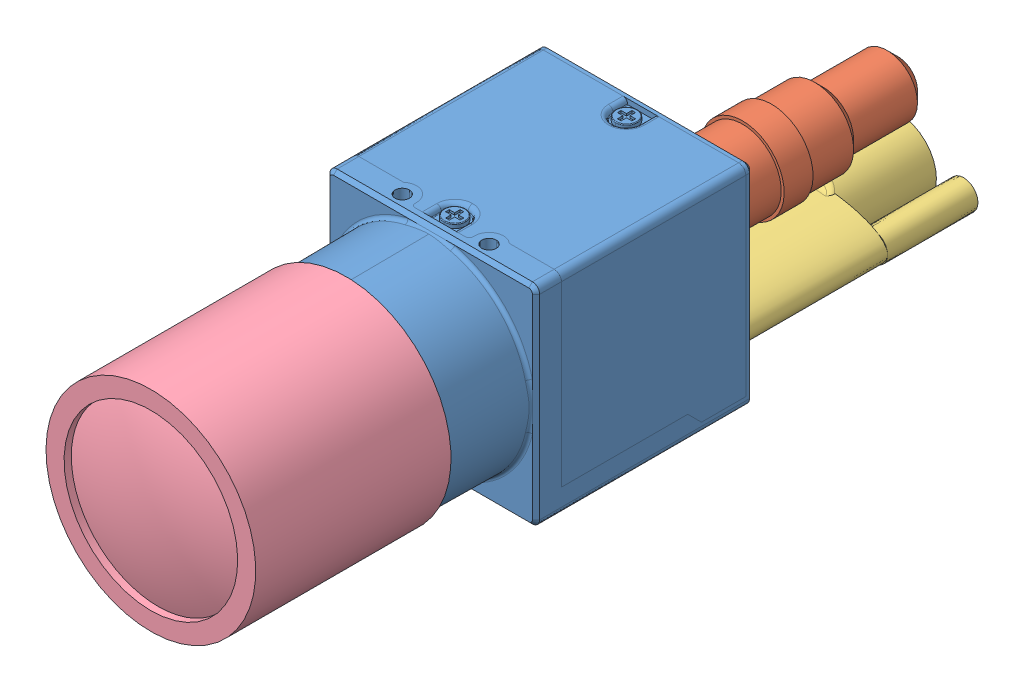
SolidWorks assembly BFS_U3_pinhole, configuration Default. Lengths in mm.
Overall size (36.71 36.71 104.36).
4 component instances, 4 part files, 9 mates.
Components (placement in the parent):
- FL2-020-R0-1: FL2-020-R0 [Default] at origin size (29 29 47.76)
- round_connector-1: round_connector [Default] at (7.25 7.25 -17.9182) x (0 0 -1) z (-0.517634 -0.855602 0) size (26.5 11.5 11.5)
- wide_connector-1: wide_connector [Default] at (0 -9.325 -18.2182) x (1 0 0) z (0 0 -1) size (22 10.5 33.5)
- Tamron_M118FM08-1: Tamron_M118FM08 [Default] at (0 0 36.6398) x (0.317874 -0.948133 0) z (0 0 1) size (29 29 34.1)
Mates (geometry in assembly coordinates):
- Coincident1: coincident anti-aligned: plane of FL2-020-R0_V2.step-1 through (-10 -7.325 -18.2182) normal (0 0 -1); plane of wide_connector-1 through (0 -9.325 -18.2182) normal (0 0 1)
- Concentric1: concentric anti-aligned: cylinder of FL2-020-R0_V2.step-1 through (-9 -9.325 -18.2182) axis (0 0 -1) radius 1; cylinder of wide_connector-1 through (-9 -9.325 -51.7182) axis (0 0 1) radius 2
- Concentric3: concentric anti-aligned: cylinder of FL2-020-R0_V2.step-1 through (9 -9.325 -18.2182) axis (0 0 -1) radius 1; cylinder of wide_connector-1 through (9 -9.325 -51.7182) axis (0 0 1) radius 2
- Concentric5: concentric aligned: circle of FL2-020-R0_V2.step-1; circle of round_connector-1
- Coincident3: coincident anti-aligned: plane of FL2-020-R0_V2.step-1 through (7.25 7.25 -17.9182) normal (0 0 -1); plane of round_connector-1 through (11.8275 4.4807 -17.9182) normal (0 0 1)
- Concentric6: concentric: cylinder of FL2-020-R0-1 through (0 0 22.9747) axis (0 0 1) radius 12.7; cylinder of FE185C086HA_1-1 through (0 0 28.9267) axis (0 0 -1) radius 11.2
- Coincident5: coincident anti-aligned: plane of FL2-020-R0-1 through (0 13.5741 24.6398) normal (0 0 1); plane of FE185C086HA_1-1 through (0 0 37.2267) normal (0 0 -1)
- Concentric7: concentric anti-aligned: cone of FL2-020-R0-1 through (0 0 13.132) axis (0 0 1); cylinder of Tamron_M111FM08_8mm-1 through (0 0 18.5398) axis (0 0 -1) radius 14.5
- Coincident6: coincident anti-aligned: plane of FL2-020-R0-1 through (0 13.5741 24.6398) normal (0 0 1); plane of Tamron_M111FM08_8mm-1 through (13.7479 4.6092 24.6398) normal (0 0 -1)
